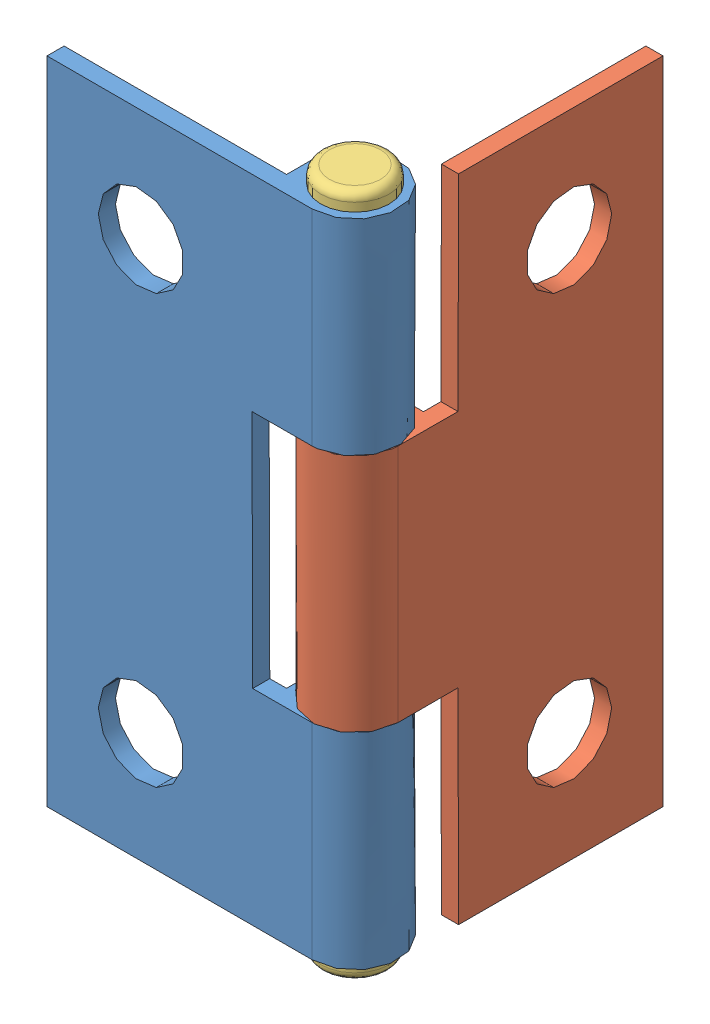
SolidWorks assembly 合叶, configuration Default. Lengths in mm.
Overall size (18 40 18).
3 component instances, 3 part files, 4 mates.
Components (placement in the parent):
- 合叶片1-1: 合叶片1 [Default] at (2.7824 21.9118 33.9517) size (18 38 5)
- 合叶片2-1: 合叶片2 [Default] at (13.2824 21.9118 23.4517) x (0 0 1) z (1 0 0) size (18 38 5)
- 合叶销-1: 合叶销 [Default] at (11.7824 1.9118 32.4517) x (0.961018 0 0.276484) z (0 1 0) size (4 4 40)
Mates (geometry in assembly coordinates):
- 同心1: concentric anti-aligned: cylinder of 合叶片1-1 through (11.7824 2.9118 32.4517) axis (0 1 0) radius 2; cylinder of 合叶片2-1 through (11.7824 40.9118 32.4517) axis (0 -1 0) radius 2
- 对称4: symmetric aligned: plane of 合叶片1-1 through (2.7824 21.9118 33.9517) normal (0 1 0); plane of 合叶片2-1 through (4.2824 28.9023 28.9326) normal (0 0.999996 -0.002722); plane of 合叶片2-1 through (4.2824 14.9214 28.9326) normal (0 -0.999996 -0.002722)
- 同心2: concentric anti-aligned: cylinder of 合叶片1-1 through (11.7824 2.9118 32.4517) axis (0 1 0) radius 2; cylinder of 合叶销-1 through (11.7824 41.9118 32.4517) axis (0 -1 0) radius 2
- 距离1: distance = 1 mm aligned: plane of 合叶销-1 through (11.7824 1.9118 32.4517) normal (0 -1 0); plane of 合叶片1-1 through (-3.7176 2.9118 34.9517) normal (0 -1 0)
